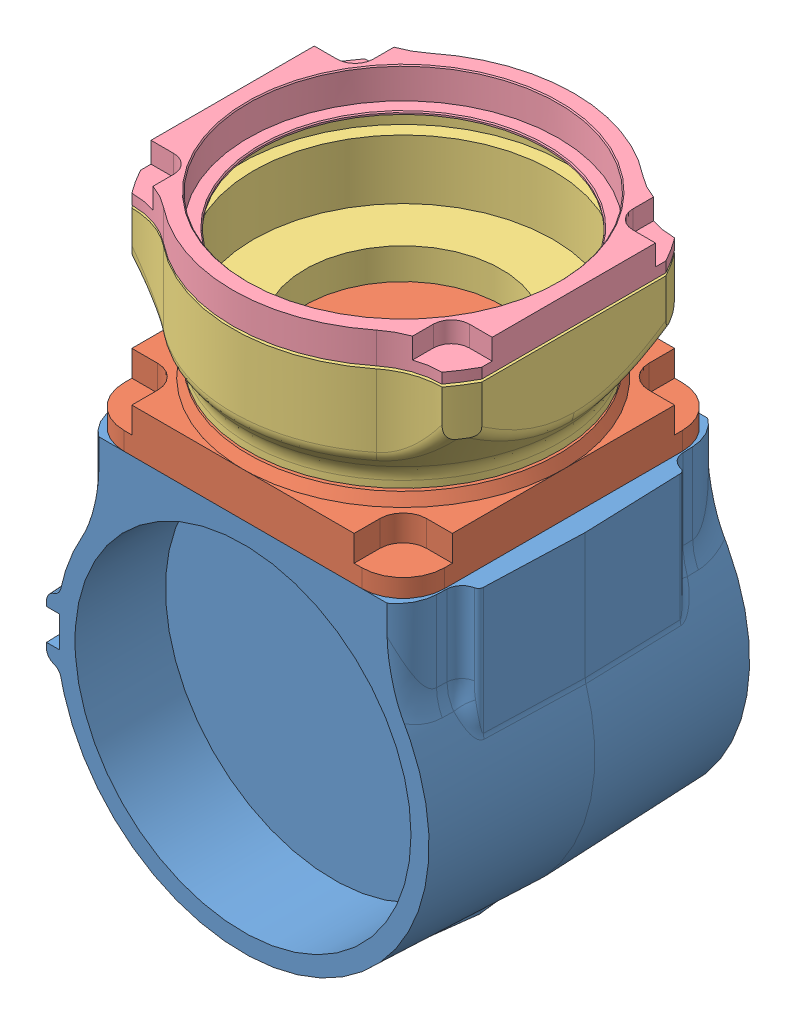
SolidWorks assembly GP7_B_AXIS, configuration Default. Lengths in mm.
Overall size (76.59 114 77.77).
4 component instances, 4 part files, 0 mates.
Components (placement in the parent):
- BAXIS_WRISTBASE-1: BAXIS_WRISTBASE [Default] at origin size (76.17 74.5 77.77)
- BAXIS_HOUSING-1: BAXIS_HOUSING [Default] at (0 36.5 0) x (1 0 0) z (0 0 -1) size (62 13 62)
- BAXIS_HOUSING2-1: BAXIS_HOUSING2 [Default] at (0 47.5 0) x (0 1 0) z (0 0 1) size (22 75.01 66)
- BAXIS_HOUSING3-1: BAXIS_HOUSING3 [Default] at (0 70 0) x (0 1 0) z (0 0 -1) size (6.5 66 66)
